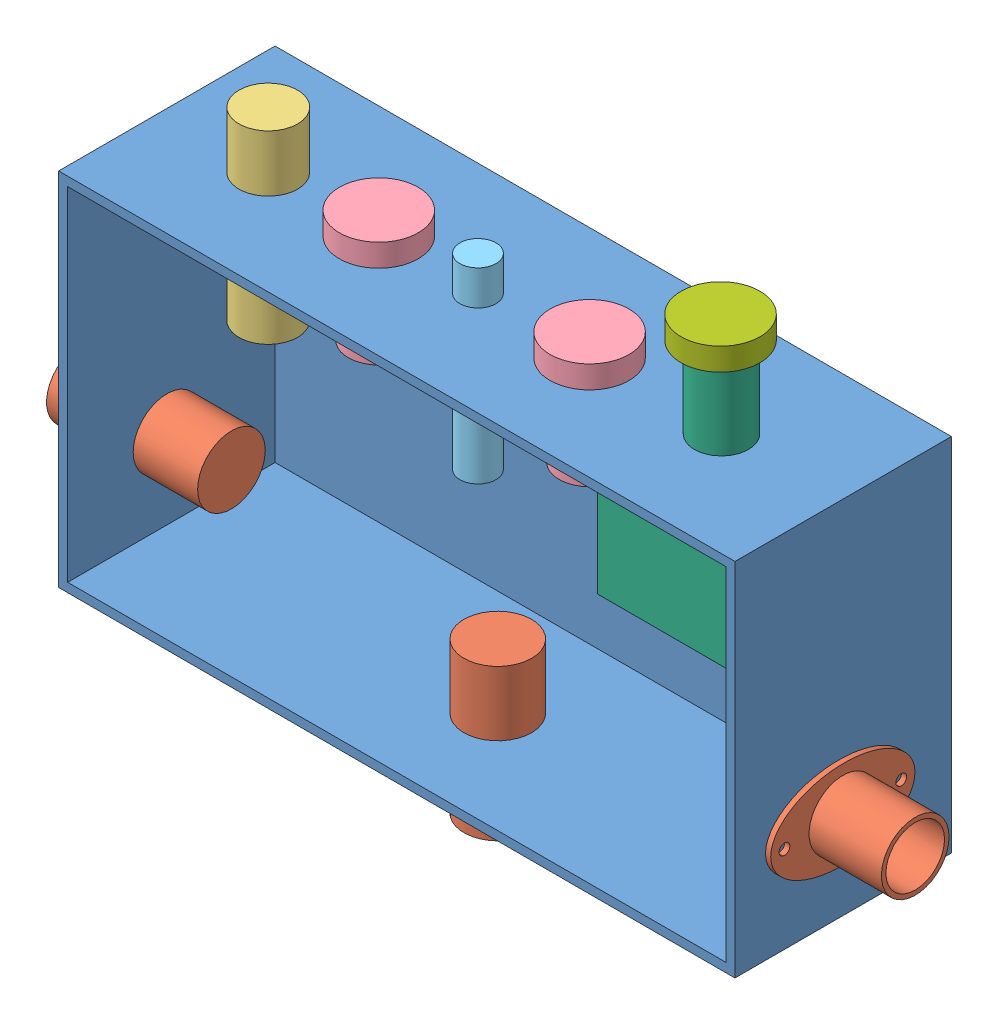
SolidWorks assembly switchbox, configuration Default. Lengths in mm.
Overall size (184.42 120.21 50).
11 component instances, 7 part files, 10 mates.
Components (placement in the parent):
- switchbox-1: switchbox [Default] at (-78.9745 42.3812 28.118) size (150 80 50)
- AS size 10_JDB-1: AS size 10_JDB [Default] at (71.0255 -17.0073 3.356) x (0 -0.999891 -0.014797) z (0 -0.014797 0.999891) size (19.5 33.5 32)
- AS size 10_JDB-2: AS size 10_JDB [Default] at (-4.1308 -37.6188 3.5705) x (0.005502 0 0.999985) z (0.999985 0 -0.005502) size (19.5 33.5 32)
- AS size 10_JDB-3: AS size 10_JDB [Default] at (-78.9745 -17.9095 4.0801) x (0 1 0) z (0 0 1) size (19.5 33.5 32)
- fuse-1: fuse [Default] at (-55.4745 54.9109 3.118) x (0.995817 0 0.091369) z (-0.091369 0 0.995817) size (13 41 13)
- estart-1: estart [Default] at (-30.9745 42.3812 3.118) x (-0.641577 0 -0.767059) z (0.767059 0 -0.641577) size (17.5 25 17.5)
- d-light-1: d-light [Default] at (-8.9745 50.0815 3.118) x (0.865774 0 -0.500435) z (0.500435 0 0.865774) size (8 41.5 8)
- estart-2: estart [Default] at (15.7755 42.3812 3.118) x (0.975409 0 0.220404) z (-0.220404 0 0.975409) size (17.5 25 17.5)
- estopcomplete-1: estopcomplete [Default] at (27.5214 30.3812 13.1108) x (1 0 0.000411) z (-0.000411 0 1) size (35 57.5 24.22)
  - Estop-1: Estop [Default] at origin size (35 52.5 20)
  - estop-top-1: estop-top [Default] at (17.364 35 -9.9351) x (-0.837169 0 -0.546944) z (-0.546944 0 0.837169) size (17.5 5 17.5)
Mates (geometry in assembly coordinates):
- Lock2: lock: unknown of switchbox-1; unknown of AS size 10_JDB-1
- Lock4: lock: unknown of switchbox-1; unknown of AS size 10_JDB-2
- Lock3: lock: unknown of switchbox-1; unknown of AS size 10_JDB-3
- Lock5: lock: unknown of switchbox-1; unknown of fuse-1
- Concentric3: concentric aligned: circle of switchbox-1; circle of estart-1
- Coincident11: coincident aligned: plane of switchbox-1 through (-78.9745 42.3812 28.118) normal (0 1 0); circle of estart-1
- Lock6: lock: unknown of switchbox-1; unknown of d-light-1
- Coincident13: coincident aligned: plane of switchbox-1 through (-78.9745 42.3812 28.118) normal (0 1 0); circle of estart-2
- Coincident14: coincident aligned: circle of switchbox-1; cylinder of estart-2 through (15.7755 22.3812 3.118) axis (0 1 0) radius 6.75
- Distance1: distance = 12 mm aligned: plane of estopcomplete-1/Estop-1 through (27.5214 30.3812 13.1108) normal (0 1 0); plane of switchbox-1 through (-78.9745 42.3812 28.118) normal (0 1 0)
